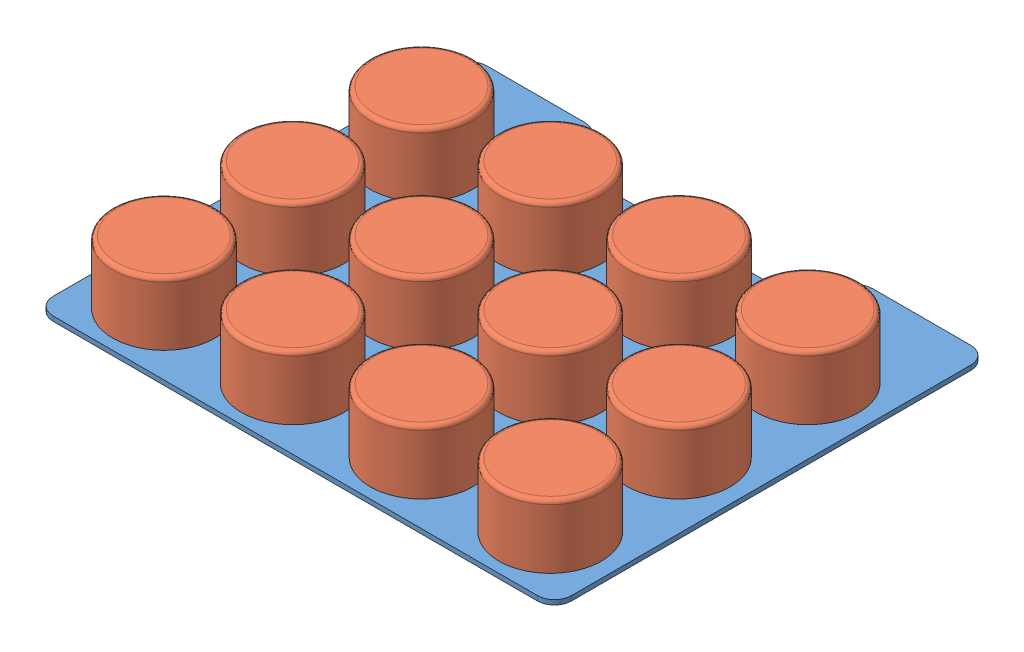
SolidWorks assembly Assem2, configuration Default. Lengths in mm.
Overall size (313.16 40.89 264.25).
13 component instances, 2 part files, 12 mates.
Components (placement in the parent):
- top-1: top [Default] at (219.2911 116.6076 426.0722) x (-1 0 0) z (0 0 1) size (309.88 2.79 259.08)
- cupcake bottom-1: cupcake bottom [Default] at (179.8068 116.6076 235.2039) x (0.920196 0 0.391459) z (-0.391459 0 0.920196) size (61.19 38.1 61.19)
- cupcake bottom-2: cupcake bottom [Default] at (179.8068 116.6076 312.1659) size (61.19 38.1 61.19)
- cupcake bottom-3: cupcake bottom [Default] at (179.8068 116.6076 389.1279) size (61.19 38.1 61.19)
- cupcake bottom-4: cupcake bottom [Default] at (102.8448 116.6076 235.2039) size (61.19 38.1 61.19)
- cupcake bottom-5: cupcake bottom [Default] at (25.8828 116.6076 235.2039) x (0.675793 0 0.737091) z (-0.737091 0 0.675793) size (61.19 38.1 61.19)
- cupcake bottom-6: cupcake bottom [Default] at (-51.0792 116.6076 235.2039) x (0.9694 0 -0.245488) z (0.245488 0 0.9694) size (61.19 38.1 61.19)
- cupcake bottom-7: cupcake bottom [Default] at (-51.0792 116.6076 312.1659) x (0.979075 0 -0.203502) z (0.203502 0 0.979075) size (61.19 38.1 61.19)
- cupcake bottom-8: cupcake bottom [Default] at (-51.1046 116.3536 389.1279) x (-0.526246 0 0.850332) z (-0.850332 0 -0.526246) size (61.19 38.1 61.19)
- cupcake bottom-9: cupcake bottom [Default] at (25.8828 116.6076 312.1659) size (61.19 38.1 61.19)
- cupcake bottom-10: cupcake bottom [Default] at (25.8828 116.6076 389.1279) size (61.19 38.1 61.19)
- cupcake bottom-11: cupcake bottom [Default] at (102.8448 116.6076 312.1659) size (61.19 38.1 61.19)
- cupcake bottom-12: cupcake bottom [Default] at (102.8448 116.6076 389.1279) size (61.19 38.1 61.19)
Mates (geometry in assembly coordinates):
- Coincident1: coincident: circle of top-1; circle of cupcake bottom-1
- Coincident2: coincident: circle of top-1; circle of cupcake bottom-2
- Coincident3: coincident: circle of top-1; circle of cupcake bottom-3
- Coincident4: coincident: circle of top-1; circle of cupcake bottom-4
- Coincident5: coincident: circle of top-1; circle of cupcake bottom-5
- Coincident6: coincident: circle of top-1; circle of cupcake bottom-6
- Coincident7: coincident: circle of top-1; circle of cupcake bottom-7
- Coincident8: coincident: circle of top-1; circle of cupcake bottom-8
- Coincident9: coincident: circle of top-1; circle of cupcake bottom-9
- Coincident10: coincident: circle of top-1; circle of cupcake bottom-10
- Coincident11: coincident: circle of top-1; circle of cupcake bottom-11
- Coincident12: coincident: circle of top-1; circle of cupcake bottom-12
